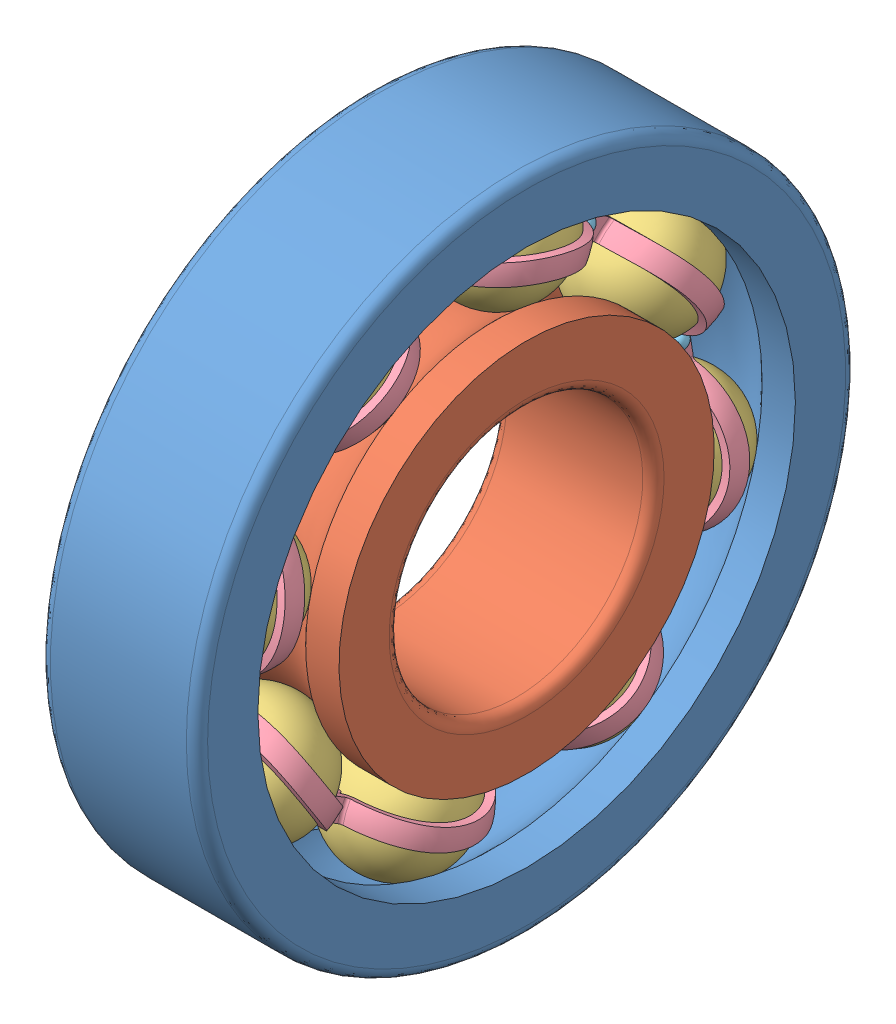
SolidWorks assembly Assem1, configuration Default. Lengths in mm.
Overall size (31 130 130).
20 component instances, 5 part files, 9 mates.
Components (placement in the parent):
- Part1-1: Part1 [Default] at (-67.5424 90.785 145.4459) size (31 130 130)
- Part2-1: Part2 [Default] at (-67.5424 90.785 145.4459) x (1 0 0) z (0 -0.976724 0.214501) size (31 74 74)
- Part3-1: Part3 [Default] at (-67.5424 100.4375 189.3984) x (1 0 0) z (0 -0.976724 0.214501) size (24 24 24)
- Part4-1: Part4 [Default] at (-59.5424 90.785 145.4459) x (0 -0.538973 0.842323) z (-1 0 0) size (94 94 13.65)
- Part3-2: Part3 [Default] at (-67.5424 128.6895 169.6996) x (1 0 0) z (0 -0.538973 0.842323) size (24 24 24)
- Part3-3: Part3 [Default] at (-67.5424 134.7375 135.7933) x (1 0 0) z (0 0.214501 0.976724) size (24 24 24)
- Part3-4: Part3 [Default] at (-67.5424 115.0387 107.5413) x (1 0 0) z (0 0.842323 0.538973) size (24 24 24)
- Part3-5: Part3 [Default] at (-67.5424 81.1324 101.4933) x (1 0 0) z (0 0.976724 -0.214501) size (24 24 24)
- Part3-6: Part3 [Default] at (-67.5424 52.8804 121.1921) x (1 0 0) z (0 0.538973 -0.842323) size (24 24 24)
- Part3-7: Part3 [Default] at (-67.5424 46.8324 155.0984) x (1 0 0) z (0 -0.214501 -0.976724) size (24 24 24)
- Part3-8: Part3 [Default] at (-67.5424 66.5312 183.3504) x (1 0 0) z (0 -0.842323 -0.538973) size (24 24 24)
- Part4-2: Part4 [Default] at (-75.5424 90.785 145.4459) x (0 0.538973 -0.842323) z (1 0 0) size (94 94 13.65)
- rivet 02_din-1: rivet 02_din [DIN 660-2x6-St-A-3] at (-69.0424 98.6871 101.1451) x (-1 0 0) z (0 0.924225 0.381849) size (5.4 3.5 3.5)
- rivet 02_din-2: rivet 02_din [DIN 660-2x6-St-A-3] at (-69.0424 65.0472 108.5329) x (-1 0 0) z (0 0.923534 -0.383517) size (5.4 3.5 3.5)
- rivet 02_din-3: rivet 02_din [DIN 660-2x6-St-A-3] at (-69.0424 46.4842 137.5438) x (-1 0 0) z (0 0.381849 -0.924225) size (5.4 3.5 3.5)
- rivet 02_din-4: rivet 02_din [DIN 660-2x6-St-A-3] at (-69.0424 53.872 171.1836) x (-1 0 0) z (0 -0.383517 -0.923534) size (5.4 3.5 3.5)
- rivet 02_din-5: rivet 02_din [DIN 660-2x6-St-A-3] at (-69.0424 82.8828 189.7466) x (-1 0 0) z (0 -0.924225 -0.381849) size (5.4 3.5 3.5)
- rivet 02_din-6: rivet 02_din [DIN 660-2x6-St-A-3] at (-69.0424 116.5227 182.3589) x (-1 0 0) z (0 -0.923534 0.383517) size (5.4 3.5 3.5)
- rivet 02_din-7: rivet 02_din [DIN 660-2x6-St-A-3] at (-69.0424 135.0857 153.348) x (-1 0 0) z (0 -0.381849 0.924225) size (5.4 3.5 3.5)
- rivet 02_din-8: rivet 02_din [DIN 660-2x6-St-A-3] at (-69.0424 127.698 119.7082) x (-1 0 0) z (0 0.383517 0.923534) size (5.4 3.5 3.5)
Mates (geometry in assembly coordinates):
- Concentric1: concentric aligned: cylinder of Part1-1 through (-81.5602 90.785 145.4459) axis (-1 0 0) radius 65; cylinder of Part2-1 through (-90.9976 90.785 145.4459) axis (-1 0 0) radius 25
- Width1: width anti-aligned: plane of Part1-1 through (-52.0424 155.785 145.4459) normal (1 0 0); plane of Part2-1 through (-83.0424 155.785 145.4459) normal (-1 0 0); plane of Part1-1 through (-83.0424 98.7215 181.5847) normal (-1 0 0); plane of Part2-1 through (-52.0424 98.7215 181.5847) normal (1 0 0)
- Coincident1: coincident aligned: plane of Part2-1 through (-67.5424 90.785 145.4459) normal (0 -0.976724 0.214501); plane of Part3-1 through (-67.5424 100.4375 189.3984) normal (0 -0.976724 0.214501)
- Coincident2: coincident aligned: plane of Part2-1 through (-67.5424 90.785 145.4459) normal (1 0 0); plane of Part3-1 through (-67.5424 100.4375 189.3984) normal (1 0 0)
- Tangent1: tangent anti-aligned: torus of Part2-1; sphere of Part3-1
- Coincident3: coincident: line of assembly; axis of Part2-1 through (-65.6066 90.785 145.4459) axis (-1 0 0); axis of Part4-1 through (-67.5424 90.785 145.4459) axis (1 0 0)
- Concentric2: concentric: sphere of Part3-1; sphere of Part4-1
- Concentric4: concentric anti-aligned: cylinder of Part4-1 through (-54.0424 98.6871 101.1451) axis (-1 0 0) radius 1; cylinder of rivet 02_din-1 through (-30.0424 98.6871 101.1451) axis (1 0 0) radius 1
- Coincident4: coincident anti-aligned: plane of Part4-1 through (-66.0424 90.785 145.4459) normal (1 0 0); plane of rivet 02_din-1 through (-66.0424 98.3052 102.0693) normal (-1 0 0)
